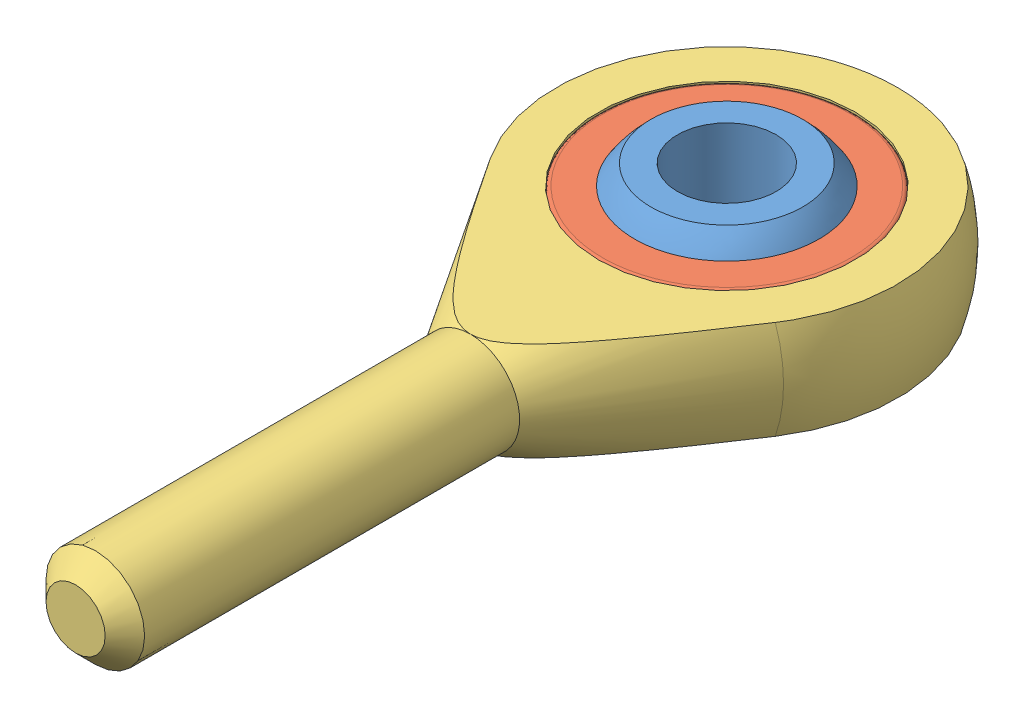
SolidWorks assembly Przegub kulowy_GN 648.2_5, configuration Domyślna. Lengths in mm.
Overall size (18 8 42).
3 component instances, 3 part files, 8 mates.
Components (placement in the parent):
- ROD-END-GN-648.2-1-5-1: ROD-END-GN-648.2-1-5 [5] x (-1 0 0) z (0 0 -1) size (11.1 8 11.1)
- ROD-END-GN-648.2-2-5-1: ROD-END-GN-648.2-2-5 [5] x (0.997964 0 0.063787) z (-0.063787 0 0.997964) size (13 6 13)
- ROD-END-GN-648.2-3-5-1: ROD-END-GN-648.2-3-5 [5] at (0 0.5 0) size (18 5 42)
Mates (geometry in assembly coordinates):
- Koncentryczne1: concentric: sphere of ROD-END-GN-648.2-2-5-1; sphere of ROD-END-GN-648.2-1-5-1
- Limit kąta1: limit planar angle = 0 rad aligned: cylinder of ROD-END-GN-648.2-1-5-1 through (0 -11.1 0) axis (0 -1 0) radius 2.5
- Limit kąta2: limit planar angle = 0 rad aligned: cylinder of ROD-END-GN-648.2-2-5-1 through (0 3 0) axis (0 -1 0) radius 6.5
- Koncentryczne5: concentric anti-aligned: cylinder of ROD-END-GN-648.2-3-5-1 through (0 -2 0) axis (0 1 0) radius 6.5; cylinder of ROD-END-GN-648.2-2-5-1 through (0 3 0) axis (0 -1 0) radius 6.5
- Wspólnie1: coincident aligned: plane of ROD-END-GN-648.2-3-5-1 through (-9 3 13) normal (0 1 0); plane of ROD-END-GN-648.2-2-5-1 through (0 3 0) normal (0 1 0)
- Wspólnie2: coincident anti-aligned: plane of ROD-END-GN-648.2-1-5-1 through (0 0 0) normal (0 0 -1)
- Wspólnie3: coincident aligned: plane of ROD-END-GN-648.2-1-5-1 through (0 0 0) normal (0 1 0)
- Wspólnie4: coincident anti-aligned: plane of ROD-END-GN-648.2-1-5-1 through (0 0 0) normal (-1 0 0)
